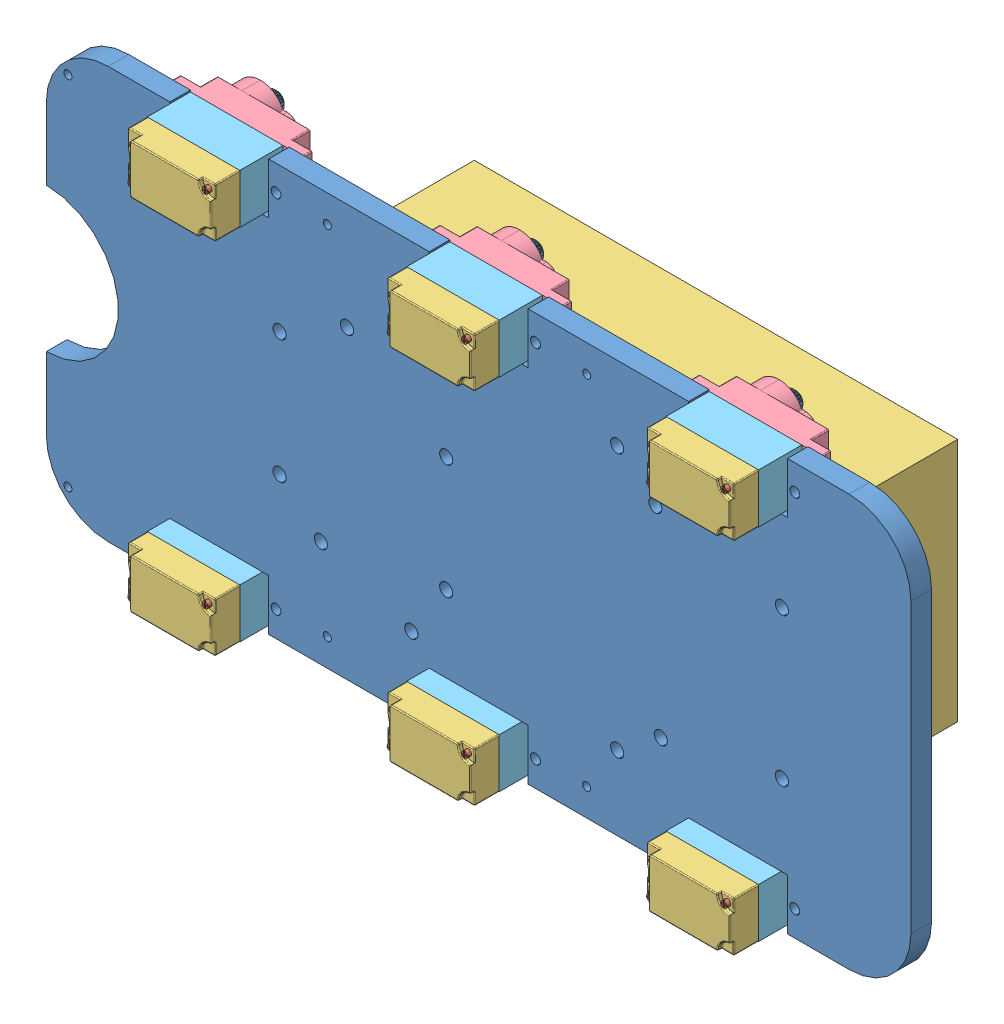
SolidWorks assembly AssembleUpperChassis, configuration Default. Lengths in mm.
Overall size (210 100.78 57.57).
129 component instances, 21 part files, 24 mates.
Components (placement in the parent):
- Chassis-1: Chassis [Default] at (89.7832 107.0664 156.8937) size (210 100 22.7)
- arduinoMega-1: arduinoMega [Detailed] at (98.4898 107.1619 156.8937) x (-0.999997 -0.002352 0) z (0.002352 -0.999997 0) size (108.32 14.5 53.3)
- MG90S-1: MG90S [Default] at (184.6156 84.5541 131.3432) x (0 -1 0) z (1 0 0) size (13.58 32.57 32)
  - MG90S.STEP-1: MG90S.STEP [Default] at origin size (13.58 32.57 32)
    - Part1.STEP-1: Part1.STEP [Default] at (21.0878 -43.0505 -32.5824) x (0 0 -1) z (1 0 0) size (22.54 9.07 12)
    - Part2.STEP-1: Part2.STEP [Default] at (21.0878 -25.5505 -32.5824) x (0 0 -1) z (1 0 0) size (32 13 12)
    - Part3.STEP-1: Part3.STEP [Default] at (21.0878 -36.0505 -32.5824) x (0 0 -1) z (1 0 0) size (22.5 16 12)
    - spur gear_iso_ISO - Spur gear 0.25M 38T 20PA 1.5FW ---S38A75H50L1.5N.STEP-1: spur gear_iso_ISO - Spur gear 0.25M 38T 20PA 1.5FW ---S38A75H50L1.5N.STEP [Default] at (21.0878 -22.3005 -37.8324) x (0 -1 0) z (0.87496 0 0.484196) size (1.5 9.98 10)
    - spur gear_iso_ISO - Spur gear 0.3M 31T 20PA 2FW ---S31A75H50L1.25N.STEP-1: spur gear_iso_ISO - Spur gear 0.3M 31T 20PA 2FW ---S31A75H50L1.25N.STEP [Default] at (21.0878 -19.8005 -31.3324) x (0 -1 0) z (0.109568 0 -0.993979) size (2 9.88 9.89)
    - spur gear_iso_ISO - Spur gear 0.4M 23T 20PA 2.75FW ---S23A75H50L1.5N.STEP-1: spur gear_iso_ISO - Spur gear 0.4M 23T 20PA 2.75FW ---S23A75H50L1.5N.STEP [Default] at (21.0878 -19.8005 -37.8324) x (0 1 0) z (-0.993238 0 0.116099) size (2.75 9.97 9.99)
    - spur gear_iso_ISO - Spur gear 0.25M 31T 20PA 1.25FW ---S31A75H50L1.25N.STEP-1: spur gear_iso_ISO - Spur gear 0.25M 31T 20PA 1.25FW ---S31A75H50L1.25N.STEP [Default] at (21.0878 -25.0505 -31.3324) x (0 1 0) z (0.977188 0 0.212376) size (1.25 8.24 8.25)
    - spur gear_iso_ISO - Spur gear 0.25M 10T 20PA 2FW ---S10A75H50L1.25N.STEP-1: spur gear_iso_ISO - Spur gear 0.25M 10T 20PA 2FW ---S10A75H50L1.25N.STEP [Default] at (21.0878 -23.8005 -31.3324) x (0 1 0) z (0.977188 0 0.212376) size (2 2.87 3)
    - gear3.STEP-1: gear3.STEP [Default] at (21.0878 -22.3005 -37.8324) x (0.87496 0 0.484196) z (-0.484196 0 0.87496) size (3.98 2.5 3.92)
    - gear1.STEP-1: gear1.STEP [Default] at (21.0878 -19.8005 -31.3324) x (0.109568 0 -0.993979) z (0.993979 0 0.109568) size (3.96 2.5 3.87)
    - gear2.STEP-1: gear2.STEP [Default] at (21.0878 -26.3005 -26.3324) x (0.891105 0 -0.453797) z (0.453797 0 0.891105) size (2.5 2.5 2.5)
    - Part4.STEP-1: Part4.STEP [Default] at (21.0878 -17.0505 -37.8324) x (0.993238 0 -0.116099) z (0.116099 0 0.993238) size (4.5 6.5 4.5)
    - Motor_Body.STEP-1: Motor_Body.STEP [Default] at (21.0878 -26.5505 -26.3324) x (-1 0 0) z (0 0 1) size (10 14.25 8)
    - Motor_Body2.STEP-1: Motor_Body2.STEP [Default] at (21.0878 -39.0505 -26.3324) size (10 2 8)
    - cilinder2.STEP-1: cilinder2.STEP [Default] at (21.0878 -31.8005 -37.8324) x (0.116099 0 0.993238) z (-0.993238 0 0.116099) size (1.5 15 1.5)
    - cilinder1.STEP-1: cilinder1.STEP [Default] at (21.0878 -27.3005 -31.3324) x (0.109568 0 -0.993979) z (0.993979 0 0.109568) size (1.25 12 1.25)
    - Part5.STEP-1: Part5.STEP [Default] at (21.0878 -40.0505 -32.0824) x (0 0 -1) z (1 0 0) size (19.28 16 10.15)
    - Part6.STEP-1: Part6.STEP [Default] at (16.5878 -42.0505 -22.8324) size (1.5 21 1.5)
    - Part6.STEP-2: Part6.STEP [Default] at (25.5878 -40.5505 -42.3324) size (1.5 21 1.5)
- MG90S-2: MG90S [Default] at (121.6156 84.5541 131.3432) x (0 -1 0) z (1 0 0) size (13.58 32.57 32)
  - MG90S.STEP-1: MG90S.STEP [Default] at origin size (13.58 32.57 32)
    - Part1.STEP-1: Part1.STEP [Default] at (21.0878 -43.0505 -32.5824) x (0 0 -1) z (1 0 0) size (22.54 9.07 12)
    - Part2.STEP-1: Part2.STEP [Default] at (21.0878 -25.5505 -32.5824) x (0 0 -1) z (1 0 0) size (32 13 12)
    - Part3.STEP-1: Part3.STEP [Default] at (21.0878 -36.0505 -32.5824) x (0 0 -1) z (1 0 0) size (22.5 16 12)
    - spur gear_iso_ISO - Spur gear 0.25M 38T 20PA 1.5FW ---S38A75H50L1.5N.STEP-1: spur gear_iso_ISO - Spur gear 0.25M 38T 20PA 1.5FW ---S38A75H50L1.5N.STEP [Default] at (21.0878 -22.3005 -37.8324) x (0 -1 0) z (0.87496 0 0.484196) size (1.5 9.98 10)
    - spur gear_iso_ISO - Spur gear 0.3M 31T 20PA 2FW ---S31A75H50L1.25N.STEP-1: spur gear_iso_ISO - Spur gear 0.3M 31T 20PA 2FW ---S31A75H50L1.25N.STEP [Default] at (21.0878 -19.8005 -31.3324) x (0 -1 0) z (0.109568 0 -0.993979) size (2 9.88 9.89)
    - spur gear_iso_ISO - Spur gear 0.4M 23T 20PA 2.75FW ---S23A75H50L1.5N.STEP-1: spur gear_iso_ISO - Spur gear 0.4M 23T 20PA 2.75FW ---S23A75H50L1.5N.STEP [Default] at (21.0878 -19.8005 -37.8324) x (0 1 0) z (-0.993238 0 0.116099) size (2.75 9.97 9.99)
    - spur gear_iso_ISO - Spur gear 0.25M 31T 20PA 1.25FW ---S31A75H50L1.25N.STEP-1: spur gear_iso_ISO - Spur gear 0.25M 31T 20PA 1.25FW ---S31A75H50L1.25N.STEP [Default] at (21.0878 -25.0505 -31.3324) x (0 1 0) z (0.977188 0 0.212376) size (1.25 8.24 8.25)
    - spur gear_iso_ISO - Spur gear 0.25M 10T 20PA 2FW ---S10A75H50L1.25N.STEP-1: spur gear_iso_ISO - Spur gear 0.25M 10T 20PA 2FW ---S10A75H50L1.25N.STEP [Default] at (21.0878 -23.8005 -31.3324) x (0 1 0) z (0.977188 0 0.212376) size (2 2.87 3)
    - gear3.STEP-1: gear3.STEP [Default] at (21.0878 -22.3005 -37.8324) x (0.87496 0 0.484196) z (-0.484196 0 0.87496) size (3.98 2.5 3.92)
    - gear1.STEP-1: gear1.STEP [Default] at (21.0878 -19.8005 -31.3324) x (0.109568 0 -0.993979) z (0.993979 0 0.109568) size (3.96 2.5 3.87)
    - gear2.STEP-1: gear2.STEP [Default] at (21.0878 -26.3005 -26.3324) x (0.891105 0 -0.453797) z (0.453797 0 0.891105) size (2.5 2.5 2.5)
    - Part4.STEP-1: Part4.STEP [Default] at (21.0878 -17.0505 -37.8324) x (0.993238 0 -0.116099) z (0.116099 0 0.993238) size (4.5 6.5 4.5)
    - Motor_Body.STEP-1: Motor_Body.STEP [Default] at (21.0878 -26.5505 -26.3324) x (-1 0 0) z (0 0 1) size (10 14.25 8)
    - Motor_Body2.STEP-1: Motor_Body2.STEP [Default] at (21.0878 -39.0505 -26.3324) size (10 2 8)
    - cilinder2.STEP-1: cilinder2.STEP [Default] at (21.0878 -31.8005 -37.8324) x (0.116099 0 0.993238) z (-0.993238 0 0.116099) size (1.5 15 1.5)
    - cilinder1.STEP-1: cilinder1.STEP [Default] at (21.0878 -27.3005 -31.3324) x (0.109568 0 -0.993979) z (0.993979 0 0.109568) size (1.25 12 1.25)
    - Part5.STEP-1: Part5.STEP [Default] at (21.0878 -40.0505 -32.0824) x (0 0 -1) z (1 0 0) size (19.28 16 10.15)
    - Part6.STEP-1: Part6.STEP [Default] at (16.5878 -42.0505 -22.8324) size (1.5 21 1.5)
    - Part6.STEP-2: Part6.STEP [Default] at (25.5878 -40.5505 -42.3324) size (1.5 21 1.5)
- MG90S-3: MG90S [Default] at (58.6156 84.5541 131.3432) x (0 -1 0) z (1 0 0) size (13.58 32.57 32)
  - MG90S.STEP-1: MG90S.STEP [Default] at origin size (13.58 32.57 32)
    - Part1.STEP-1: Part1.STEP [Default] at (21.0878 -43.0505 -32.5824) x (0 0 -1) z (1 0 0) size (22.54 9.07 12)
    - Part2.STEP-1: Part2.STEP [Default] at (21.0878 -25.5505 -32.5824) x (0 0 -1) z (1 0 0) size (32 13 12)
    - Part3.STEP-1: Part3.STEP [Default] at (21.0878 -36.0505 -32.5824) x (0 0 -1) z (1 0 0) size (22.5 16 12)
    - spur gear_iso_ISO - Spur gear 0.25M 38T 20PA 1.5FW ---S38A75H50L1.5N.STEP-1: spur gear_iso_ISO - Spur gear 0.25M 38T 20PA 1.5FW ---S38A75H50L1.5N.STEP [Default] at (21.0878 -22.3005 -37.8324) x (0 -1 0) z (0.87496 0 0.484196) size (1.5 9.98 10)
    - spur gear_iso_ISO - Spur gear 0.3M 31T 20PA 2FW ---S31A75H50L1.25N.STEP-1: spur gear_iso_ISO - Spur gear 0.3M 31T 20PA 2FW ---S31A75H50L1.25N.STEP [Default] at (21.0878 -19.8005 -31.3324) x (0 -1 0) z (0.109568 0 -0.993979) size (2 9.88 9.89)
    - spur gear_iso_ISO - Spur gear 0.4M 23T 20PA 2.75FW ---S23A75H50L1.5N.STEP-1: spur gear_iso_ISO - Spur gear 0.4M 23T 20PA 2.75FW ---S23A75H50L1.5N.STEP [Default] at (21.0878 -19.8005 -37.8324) x (0 1 0) z (-0.993238 0 0.116099) size (2.75 9.97 9.99)
    - spur gear_iso_ISO - Spur gear 0.25M 31T 20PA 1.25FW ---S31A75H50L1.25N.STEP-1: spur gear_iso_ISO - Spur gear 0.25M 31T 20PA 1.25FW ---S31A75H50L1.25N.STEP [Default] at (21.0878 -25.0505 -31.3324) x (0 1 0) z (0.977188 0 0.212376) size (1.25 8.24 8.25)
    - spur gear_iso_ISO - Spur gear 0.25M 10T 20PA 2FW ---S10A75H50L1.25N.STEP-1: spur gear_iso_ISO - Spur gear 0.25M 10T 20PA 2FW ---S10A75H50L1.25N.STEP [Default] at (21.0878 -23.8005 -31.3324) x (0 1 0) z (0.977188 0 0.212376) size (2 2.87 3)
    - gear3.STEP-1: gear3.STEP [Default] at (21.0878 -22.3005 -37.8324) x (0.87496 0 0.484196) z (-0.484196 0 0.87496) size (3.98 2.5 3.92)
    - gear1.STEP-1: gear1.STEP [Default] at (21.0878 -19.8005 -31.3324) x (0.109568 0 -0.993979) z (0.993979 0 0.109568) size (3.96 2.5 3.87)
    - gear2.STEP-1: gear2.STEP [Default] at (21.0878 -26.3005 -26.3324) x (0.891105 0 -0.453797) z (0.453797 0 0.891105) size (2.5 2.5 2.5)
    - Part4.STEP-1: Part4.STEP [Default] at (21.0878 -17.0505 -37.8324) x (0.993238 0 -0.116099) z (0.116099 0 0.993238) size (4.5 6.5 4.5)
    - Motor_Body.STEP-1: Motor_Body.STEP [Default] at (21.0878 -26.5505 -26.3324) x (-1 0 0) z (0 0 1) size (10 14.25 8)
    - Motor_Body2.STEP-1: Motor_Body2.STEP [Default] at (21.0878 -39.0505 -26.3324) size (10 2 8)
    - cilinder2.STEP-1: cilinder2.STEP [Default] at (21.0878 -31.8005 -37.8324) x (0.116099 0 0.993238) z (-0.993238 0 0.116099) size (1.5 15 1.5)
    - cilinder1.STEP-1: cilinder1.STEP [Default] at (21.0878 -27.3005 -31.3324) x (0.109568 0 -0.993979) z (0.993979 0 0.109568) size (1.25 12 1.25)
    - Part5.STEP-1: Part5.STEP [Default] at (21.0878 -40.0505 -32.0824) x (0 0 -1) z (1 0 0) size (19.28 16 10.15)
    - Part6.STEP-1: Part6.STEP [Default] at (16.5878 -42.0505 -22.8324) size (1.5 21 1.5)
    - Part6.STEP-2: Part6.STEP [Default] at (25.5878 -40.5505 -42.3324) size (1.5 21 1.5)
- MG90S-4: MG90S [Default] at (58.6156 171.7541 131.3432) x (0 -1 0) z (1 0 0) size (13.58 32.57 32)
  - MG90S.STEP-1: MG90S.STEP [Default] at origin size (13.58 32.57 32)
    - Part1.STEP-1: Part1.STEP [Default] at (21.0878 -43.0505 -32.5824) x (0 0 -1) z (1 0 0) size (22.54 9.07 12)
    - Part2.STEP-1: Part2.STEP [Default] at (21.0878 -25.5505 -32.5824) x (0 0 -1) z (1 0 0) size (32 13 12)
    - Part3.STEP-1: Part3.STEP [Default] at (21.0878 -36.0505 -32.5824) x (0 0 -1) z (1 0 0) size (22.5 16 12)
    - spur gear_iso_ISO - Spur gear 0.25M 38T 20PA 1.5FW ---S38A75H50L1.5N.STEP-1: spur gear_iso_ISO - Spur gear 0.25M 38T 20PA 1.5FW ---S38A75H50L1.5N.STEP [Default] at (21.0878 -22.3005 -37.8324) x (0 -1 0) z (0.87496 0 0.484196) size (1.5 9.98 10)
    - spur gear_iso_ISO - Spur gear 0.3M 31T 20PA 2FW ---S31A75H50L1.25N.STEP-1: spur gear_iso_ISO - Spur gear 0.3M 31T 20PA 2FW ---S31A75H50L1.25N.STEP [Default] at (21.0878 -19.8005 -31.3324) x (0 -1 0) z (0.109568 0 -0.993979) size (2 9.88 9.89)
    - spur gear_iso_ISO - Spur gear 0.4M 23T 20PA 2.75FW ---S23A75H50L1.5N.STEP-1: spur gear_iso_ISO - Spur gear 0.4M 23T 20PA 2.75FW ---S23A75H50L1.5N.STEP [Default] at (21.0878 -19.8005 -37.8324) x (0 1 0) z (-0.993238 0 0.116099) size (2.75 9.97 9.99)
    - spur gear_iso_ISO - Spur gear 0.25M 31T 20PA 1.25FW ---S31A75H50L1.25N.STEP-1: spur gear_iso_ISO - Spur gear 0.25M 31T 20PA 1.25FW ---S31A75H50L1.25N.STEP [Default] at (21.0878 -25.0505 -31.3324) x (0 1 0) z (0.977188 0 0.212376) size (1.25 8.24 8.25)
    - spur gear_iso_ISO - Spur gear 0.25M 10T 20PA 2FW ---S10A75H50L1.25N.STEP-1: spur gear_iso_ISO - Spur gear 0.25M 10T 20PA 2FW ---S10A75H50L1.25N.STEP [Default] at (21.0878 -23.8005 -31.3324) x (0 1 0) z (0.977188 0 0.212376) size (2 2.87 3)
    - gear3.STEP-1: gear3.STEP [Default] at (21.0878 -22.3005 -37.8324) x (0.87496 0 0.484196) z (-0.484196 0 0.87496) size (3.98 2.5 3.92)
    - gear1.STEP-1: gear1.STEP [Default] at (21.0878 -19.8005 -31.3324) x (0.109568 0 -0.993979) z (0.993979 0 0.109568) size (3.96 2.5 3.87)
    - gear2.STEP-1: gear2.STEP [Default] at (21.0878 -26.3005 -26.3324) x (0.891105 0 -0.453797) z (0.453797 0 0.891105) size (2.5 2.5 2.5)
    - Part4.STEP-1: Part4.STEP [Default] at (21.0878 -17.0505 -37.8324) x (0.993238 0 -0.116099) z (0.116099 0 0.993238) size (4.5 6.5 4.5)
    - Motor_Body.STEP-1: Motor_Body.STEP [Default] at (21.0878 -26.5505 -26.3324) x (-1 0 0) z (0 0 1) size (10 14.25 8)
    - Motor_Body2.STEP-1: Motor_Body2.STEP [Default] at (21.0878 -39.0505 -26.3324) size (10 2 8)
    - cilinder2.STEP-1: cilinder2.STEP [Default] at (21.0878 -31.8005 -37.8324) x (0.116099 0 0.993238) z (-0.993238 0 0.116099) size (1.5 15 1.5)
    - cilinder1.STEP-1: cilinder1.STEP [Default] at (21.0878 -27.3005 -31.3324) x (0.109568 0 -0.993979) z (0.993979 0 0.109568) size (1.25 12 1.25)
    - Part5.STEP-1: Part5.STEP [Default] at (21.0878 -40.0505 -32.0824) x (0 0 -1) z (1 0 0) size (19.28 16 10.15)
    - Part6.STEP-1: Part6.STEP [Default] at (16.5878 -42.0505 -22.8324) size (1.5 21 1.5)
    - Part6.STEP-2: Part6.STEP [Default] at (25.5878 -40.5505 -42.3324) size (1.5 21 1.5)
- MG90S-5: MG90S [Default] at (121.6156 171.7541 131.3432) x (0 -1 0) z (1 0 0) size (13.58 32.57 32)
  - MG90S.STEP-1: MG90S.STEP [Default] at origin size (13.58 32.57 32)
    - Part1.STEP-1: Part1.STEP [Default] at (21.0878 -43.0505 -32.5824) x (0 0 -1) z (1 0 0) size (22.54 9.07 12)
    - Part2.STEP-1: Part2.STEP [Default] at (21.0878 -25.5505 -32.5824) x (0 0 -1) z (1 0 0) size (32 13 12)
    - Part3.STEP-1: Part3.STEP [Default] at (21.0878 -36.0505 -32.5824) x (0 0 -1) z (1 0 0) size (22.5 16 12)
    - spur gear_iso_ISO - Spur gear 0.25M 38T 20PA 1.5FW ---S38A75H50L1.5N.STEP-1: spur gear_iso_ISO - Spur gear 0.25M 38T 20PA 1.5FW ---S38A75H50L1.5N.STEP [Default] at (21.0878 -22.3005 -37.8324) x (0 -1 0) z (0.87496 0 0.484196) size (1.5 9.98 10)
    - spur gear_iso_ISO - Spur gear 0.3M 31T 20PA 2FW ---S31A75H50L1.25N.STEP-1: spur gear_iso_ISO - Spur gear 0.3M 31T 20PA 2FW ---S31A75H50L1.25N.STEP [Default] at (21.0878 -19.8005 -31.3324) x (0 -1 0) z (0.109568 0 -0.993979) size (2 9.88 9.89)
    - spur gear_iso_ISO - Spur gear 0.4M 23T 20PA 2.75FW ---S23A75H50L1.5N.STEP-1: spur gear_iso_ISO - Spur gear 0.4M 23T 20PA 2.75FW ---S23A75H50L1.5N.STEP [Default] at (21.0878 -19.8005 -37.8324) x (0 1 0) z (-0.993238 0 0.116099) size (2.75 9.97 9.99)
    - spur gear_iso_ISO - Spur gear 0.25M 31T 20PA 1.25FW ---S31A75H50L1.25N.STEP-1: spur gear_iso_ISO - Spur gear 0.25M 31T 20PA 1.25FW ---S31A75H50L1.25N.STEP [Default] at (21.0878 -25.0505 -31.3324) x (0 1 0) z (0.977188 0 0.212376) size (1.25 8.24 8.25)
    - spur gear_iso_ISO - Spur gear 0.25M 10T 20PA 2FW ---S10A75H50L1.25N.STEP-1: spur gear_iso_ISO - Spur gear 0.25M 10T 20PA 2FW ---S10A75H50L1.25N.STEP [Default] at (21.0878 -23.8005 -31.3324) x (0 1 0) z (0.977188 0 0.212376) size (2 2.87 3)
    - gear3.STEP-1: gear3.STEP [Default] at (21.0878 -22.3005 -37.8324) x (0.87496 0 0.484196) z (-0.484196 0 0.87496) size (3.98 2.5 3.92)
    - gear1.STEP-1: gear1.STEP [Default] at (21.0878 -19.8005 -31.3324) x (0.109568 0 -0.993979) z (0.993979 0 0.109568) size (3.96 2.5 3.87)
    - gear2.STEP-1: gear2.STEP [Default] at (21.0878 -26.3005 -26.3324) x (0.891105 0 -0.453797) z (0.453797 0 0.891105) size (2.5 2.5 2.5)
    - Part4.STEP-1: Part4.STEP [Default] at (21.0878 -17.0505 -37.8324) x (0.993238 0 -0.116099) z (0.116099 0 0.993238) size (4.5 6.5 4.5)
    - Motor_Body.STEP-1: Motor_Body.STEP [Default] at (21.0878 -26.5505 -26.3324) x (-1 0 0) z (0 0 1) size (10 14.25 8)
    - Motor_Body2.STEP-1: Motor_Body2.STEP [Default] at (21.0878 -39.0505 -26.3324) size (10 2 8)
    - cilinder2.STEP-1: cilinder2.STEP [Default] at (21.0878 -31.8005 -37.8324) x (0.116099 0 0.993238) z (-0.993238 0 0.116099) size (1.5 15 1.5)
    - cilinder1.STEP-1: cilinder1.STEP [Default] at (21.0878 -27.3005 -31.3324) x (0.109568 0 -0.993979) z (0.993979 0 0.109568) size (1.25 12 1.25)
    - Part5.STEP-1: Part5.STEP [Default] at (21.0878 -40.0505 -32.0824) x (0 0 -1) z (1 0 0) size (19.28 16 10.15)
    - Part6.STEP-1: Part6.STEP [Default] at (16.5878 -42.0505 -22.8324) size (1.5 21 1.5)
    - Part6.STEP-2: Part6.STEP [Default] at (25.5878 -40.5505 -42.3324) size (1.5 21 1.5)
- MG90S-6: MG90S [Default] at (184.6156 171.7541 131.3432) x (0 -1 0) z (1 0 0) size (13.58 32.57 32)
  - MG90S.STEP-1: MG90S.STEP [Default] at origin size (13.58 32.57 32)
    - Part1.STEP-1: Part1.STEP [Default] at (21.0878 -43.0505 -32.5824) x (0 0 -1) z (1 0 0) size (22.54 9.07 12)
    - Part2.STEP-1: Part2.STEP [Default] at (21.0878 -25.5505 -32.5824) x (0 0 -1) z (1 0 0) size (32 13 12)
    - Part3.STEP-1: Part3.STEP [Default] at (21.0878 -36.0505 -32.5824) x (0 0 -1) z (1 0 0) size (22.5 16 12)
    - spur gear_iso_ISO - Spur gear 0.25M 38T 20PA 1.5FW ---S38A75H50L1.5N.STEP-1: spur gear_iso_ISO - Spur gear 0.25M 38T 20PA 1.5FW ---S38A75H50L1.5N.STEP [Default] at (21.0878 -22.3005 -37.8324) x (0 -1 0) z (0.87496 0 0.484196) size (1.5 9.98 10)
    - spur gear_iso_ISO - Spur gear 0.3M 31T 20PA 2FW ---S31A75H50L1.25N.STEP-1: spur gear_iso_ISO - Spur gear 0.3M 31T 20PA 2FW ---S31A75H50L1.25N.STEP [Default] at (21.0878 -19.8005 -31.3324) x (0 -1 0) z (0.109568 0 -0.993979) size (2 9.88 9.89)
    - spur gear_iso_ISO - Spur gear 0.4M 23T 20PA 2.75FW ---S23A75H50L1.5N.STEP-1: spur gear_iso_ISO - Spur gear 0.4M 23T 20PA 2.75FW ---S23A75H50L1.5N.STEP [Default] at (21.0878 -19.8005 -37.8324) x (0 1 0) z (-0.993238 0 0.116099) size (2.75 9.97 9.99)
    - spur gear_iso_ISO - Spur gear 0.25M 31T 20PA 1.25FW ---S31A75H50L1.25N.STEP-1: spur gear_iso_ISO - Spur gear 0.25M 31T 20PA 1.25FW ---S31A75H50L1.25N.STEP [Default] at (21.0878 -25.0505 -31.3324) x (0 1 0) z (0.977188 0 0.212376) size (1.25 8.24 8.25)
    - spur gear_iso_ISO - Spur gear 0.25M 10T 20PA 2FW ---S10A75H50L1.25N.STEP-1: spur gear_iso_ISO - Spur gear 0.25M 10T 20PA 2FW ---S10A75H50L1.25N.STEP [Default] at (21.0878 -23.8005 -31.3324) x (0 1 0) z (0.977188 0 0.212376) size (2 2.87 3)
    - gear3.STEP-1: gear3.STEP [Default] at (21.0878 -22.3005 -37.8324) x (0.87496 0 0.484196) z (-0.484196 0 0.87496) size (3.98 2.5 3.92)
    - gear1.STEP-1: gear1.STEP [Default] at (21.0878 -19.8005 -31.3324) x (0.109568 0 -0.993979) z (0.993979 0 0.109568) size (3.96 2.5 3.87)
    - gear2.STEP-1: gear2.STEP [Default] at (21.0878 -26.3005 -26.3324) x (0.891105 0 -0.453797) z (0.453797 0 0.891105) size (2.5 2.5 2.5)
    - Part4.STEP-1: Part4.STEP [Default] at (21.0878 -17.0505 -37.8324) x (0.993238 0 -0.116099) z (0.116099 0 0.993238) size (4.5 6.5 4.5)
    - Motor_Body.STEP-1: Motor_Body.STEP [Default] at (21.0878 -26.5505 -26.3324) x (-1 0 0) z (0 0 1) size (10 14.25 8)
    - Motor_Body2.STEP-1: Motor_Body2.STEP [Default] at (21.0878 -39.0505 -26.3324) size (10 2 8)
    - cilinder2.STEP-1: cilinder2.STEP [Default] at (21.0878 -31.8005 -37.8324) x (0.116099 0 0.993238) z (-0.993238 0 0.116099) size (1.5 15 1.5)
    - cilinder1.STEP-1: cilinder1.STEP [Default] at (21.0878 -27.3005 -31.3324) x (0.109568 0 -0.993979) z (0.993979 0 0.109568) size (1.25 12 1.25)
    - Part5.STEP-1: Part5.STEP [Default] at (21.0878 -40.0505 -32.0824) x (0 0 -1) z (1 0 0) size (19.28 16 10.15)
    - Part6.STEP-1: Part6.STEP [Default] at (16.5878 -42.0505 -22.8324) size (1.5 21 1.5)
    - Part6.STEP-2: Part6.STEP [Default] at (25.5878 -40.5505 -42.3324) size (1.5 21 1.5)
- ArduinoCover-1: ArduinoCover [Default] at (102.4332 107.0664 116.8937) x (-1 0 0) z (0 1 0) size (126 40 68)
Mates (geometry in assembly coordinates):
- Concentric1: concentric aligned: cylinder of Chassis-1 through (57.8132 131.1764 166.8937) axis (0 0 -1) radius 1.6; cylinder of arduinoMega-1 through (57.8132 131.1764 156.8937) axis (0 0 -1) radius 1.6
- Coincident7: coincident anti-aligned: plane of Chassis-1 through (-0.2168 72.0664 156.8937) normal (0 0 -1); plane of arduinoMega-1 through (98.4898 107.1619 156.8937) normal (0 0 1)
- Parallel1: parallel aligned: cylinder of Chassis-1 through (134.0232 82.9564 166.8937) axis (0 0 -1) radius 1.6; cylinder of arduinoMega-1 through (134.0364 83.1355 156.8937) axis (0 0 -1) radius 1.6
- Coincident13: coincident anti-aligned: plane of Chassis-1 through (140.7832 69.4664 156.8937) normal (0 -1 0); plane of MG90S-1/MG90S.STEP-1/Part2.STEP-1 through (140.7832 69.4664 150.3937) normal (0 1 0)
- Coincident14: coincident anti-aligned: plane of Chassis-1 through (-0.2168 72.0664 156.8937) normal (0 0 -1); plane of MG90S-1/MG90S.STEP-1/Part2.STEP-1 through (152.0332 63.4664 156.8937) normal (0 0 1)
- Coincident15: coincident anti-aligned: plane of Chassis-1 through (140.7832 57.0664 156.8937) normal (1 0 0); plane of MG90S-1/MG90S.STEP-1/Part3.STEP-1 through (140.7832 57.4664 156.8937) normal (-1 0 0)
- Coincident19: coincident anti-aligned: plane of Chassis-1 through (77.7832 57.0664 156.8937) normal (1 0 0); plane of MG90S-2/MG90S.STEP-1/Part3.STEP-1 through (77.7832 57.4664 156.8937) normal (-1 0 0)
- Coincident20: coincident anti-aligned: plane of Chassis-1 through (77.7832 69.4664 156.8937) normal (0 -1 0); plane of MG90S-2/MG90S.STEP-1/Part3.STEP-1 through (77.7832 69.4664 156.8937) normal (0 1 0)
- Coincident22: coincident anti-aligned: plane of Chassis-1 through (-0.2168 72.0664 156.8937) normal (0 0 -1); plane of MG90S-2/MG90S.STEP-1/Part2.STEP-1 through (89.0332 63.4664 156.8937) normal (0 0 1)
- Coincident23: coincident anti-aligned: plane of Chassis-1 through (14.7832 69.4664 156.8937) normal (0 -1 0); plane of MG90S-3/MG90S.STEP-1/Part2.STEP-1 through (14.7832 69.4664 150.3937) normal (0 1 0)
- Coincident24: coincident anti-aligned: plane of Chassis-1 through (-0.2168 72.0664 156.8937) normal (0 0 -1); plane of MG90S-3/MG90S.STEP-1/Part2.STEP-1 through (26.0332 63.4664 156.8937) normal (0 0 1)
- Coincident25: coincident anti-aligned: plane of Chassis-1 through (14.7832 57.0664 156.8937) normal (1 0 0); plane of MG90S-3/MG90S.STEP-1/Part3.STEP-1 through (14.7832 57.4664 156.8937) normal (-1 0 0)
- Coincident26: coincident anti-aligned: plane of Chassis-1 through (14.7832 144.6664 156.8937) normal (0 1 0); plane of MG90S-4/MG90S.STEP-1/Part3.STEP-1 through (14.7832 144.6664 156.8937) normal (0 -1 0)
- Coincident27: coincident anti-aligned: plane of Chassis-1 through (77.7832 144.6664 156.8937) normal (0 1 0); plane of MG90S-5/MG90S.STEP-1/Part3.STEP-1 through (77.7832 144.6664 156.8937) normal (0 -1 0)
- Coincident28: coincident anti-aligned: plane of Chassis-1 through (140.7832 144.6664 156.8937) normal (0 1 0); plane of MG90S-6/MG90S.STEP-1/Part3.STEP-1 through (140.7832 144.6664 156.8937) normal (0 -1 0)
- Coincident29: coincident anti-aligned: plane of Chassis-1 through (-0.2168 72.0664 156.8937) normal (0 0 -1); plane of MG90S-4/MG90S.STEP-1/Part2.STEP-1 through (26.0332 150.6664 156.8937) normal (0 0 1)
- Coincident30: coincident anti-aligned: plane of Chassis-1 through (-0.2168 72.0664 156.8937) normal (0 0 -1); plane of MG90S-5/MG90S.STEP-1/Part2.STEP-1 through (89.0332 150.6664 156.8937) normal (0 0 1)
- Coincident31: coincident anti-aligned: plane of Chassis-1 through (-0.2168 72.0664 156.8937) normal (0 0 -1); plane of MG90S-6/MG90S.STEP-1/Part2.STEP-1 through (152.0332 150.6664 156.8937) normal (0 0 1)
- Coincident32: coincident anti-aligned: plane of Chassis-1 through (14.7832 157.0664 156.8937) normal (1 0 0); plane of MG90S-4/MG90S.STEP-1/Part3.STEP-1 through (14.7832 144.6664 156.8937) normal (-1 0 0)
- Coincident33: coincident anti-aligned: plane of Chassis-1 through (77.7832 157.0664 156.8937) normal (1 0 0); plane of MG90S-5/MG90S.STEP-1/Part3.STEP-1 through (77.7832 144.6664 156.8937) normal (-1 0 0)
- Coincident34: coincident anti-aligned: plane of Chassis-1 through (140.7832 157.0664 156.8937) normal (1 0 0); plane of MG90S-6/MG90S.STEP-1/Part3.STEP-1 through (140.7832 144.6664 156.8937) normal (-1 0 0)
- Coincident35: coincident anti-aligned: plane of Chassis-1 through (-0.2168 72.0664 156.8937) normal (0 0 -1); plane of ArduinoCover-1 through (102.4332 107.0664 156.8937) normal (0 0 1)
- Concentric2: concentric aligned: cylinder of Chassis-1 through (41.4332 92.0664 166.8937) axis (0 0 -1) radius 1.6; cylinder of ArduinoCover-1 through (41.4332 92.0664 156.8937) axis (0 0 -1) radius 1.6
- Concentric3: concentric aligned: cylinder of Chassis-1 through (163.4332 125.0664 166.8937) axis (0 0 -1) radius 1.6; cylinder of ArduinoCover-1 through (163.4332 125.0664 156.8937) axis (0 0 -1) radius 1.6
